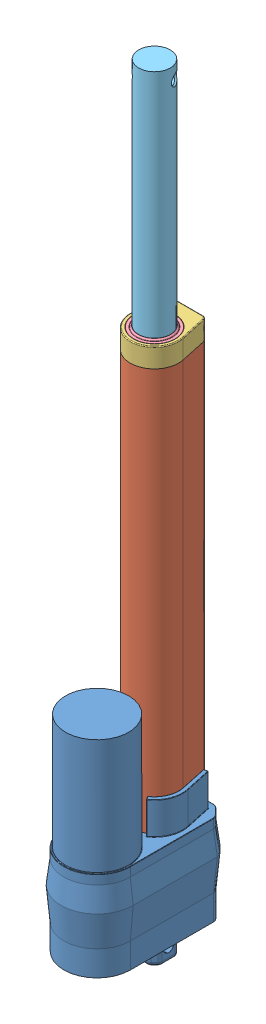
SolidWorks assembly HDA-8-2, configuration Default. Lengths in mm.
5 component instances, 5 part files, 10 mates.
Components (placement in the parent):
- HDA-BASE-1: HDA-BASE [Default] at origin size (45.73 149.35 84.91)
- HDA-SHROUD-1: HDA-SHROUD [8IN] at (0 56.642 0) size (30.48 141.15 36.83)
- HDA-SHROUD-CAP-2: HDA-SHROUD-CAP [Default] at (0 310.642 0) size (30.48 12.19 36.83)
- HDA-CAP-SEAL-1: HDA-CAP-SEAL [Default] at (0 320.294 0) size (26.42 3.52 26.42)
- HDA-STROKE-1: HDA-STROKE [8IN] at (0 469.2653 0) x (0.47376 0 0.880654) z (0.880654 0 -0.47376) size (19.94 220.98 20.14)
Mates (geometry in assembly coordinates):
- Coincident1: coincident anti-aligned: plane of HDA-BASE-1 through (0 56.642 36.195) normal (0 1 0); plane of HDA-SHROUD-1 through (0 56.642 0) normal (0 -1 0)
- Concentric1: concentric aligned: cylinder of HDA-BASE-1 through (0 76.962 0) axis (0 -1 0) radius 15.24; cylinder of HDA-SHROUD-1 through (0 107.442 0) axis (0 -1 0) radius 15.24
- Coincident2: coincident anti-aligned: plane of HDA-SHROUD-CAP-2 through (0 310.642 0) normal (0 -1 0); plane of HDA-SHROUD-1 through (8.8727 310.642 -19.05) normal (0 1 0)
- Concentric2: concentric: cylinder of HDA-SHROUD-1 through (0 107.442 0) axis (0 -1 0) radius 15.24; cylinder of HDA-SHROUD-CAP-2 through (0 322.834 0) axis (0 -1 0) radius 15.24
- Coincident3: coincident: plane of HDA-SHROUD-CAP-2 through (0 320.294 0) normal (0 1 0); plane of HDA-CAP-SEAL-1 through (-13.208 320.294 0) normal (0 -1 0)
- Concentric4: concentric: cylinder of HDA-SHROUD-CAP-2 through (0 320.294 0) axis (0 1 0) radius 13.208; cylinder of HDA-CAP-SEAL-1 through (0 320.294 0) axis (0 -1 0) radius 13.208
- Concentric5: concentric aligned: cylinder of HDA-STROKE-1 through (0 451.4853 0) axis (0 1 0) radius 9.9695; cylinder of HDA-SHROUD-CAP-2 through (0 310.642 0) axis (0 1 0) radius 9.9695
- LimitDistance1: limit distance = 146.4313 mm aligned: plane of HDA-STROKE-1 through (0 469.2653 0) normal (0 1 0); plane of HDA-SHROUD-CAP-2 through (0 322.834 0) normal (0 1 0)
- Coincident5: coincident aligned: plane of HDA-SHROUD-1 through (-10.922 107.442 -21.59) normal (0 0 -1); plane of HDA-SHROUD-CAP-2 through (-10.922 322.834 -21.59) normal (0 0 -1)
- Parallel3: parallel aligned: plane of HDA-BASE-1 through (-14.605 56.642 -24.13) normal (0 0 -1); plane of HDA-SHROUD-1 through (-10.922 107.442 -21.59) normal (0 0 -1)
